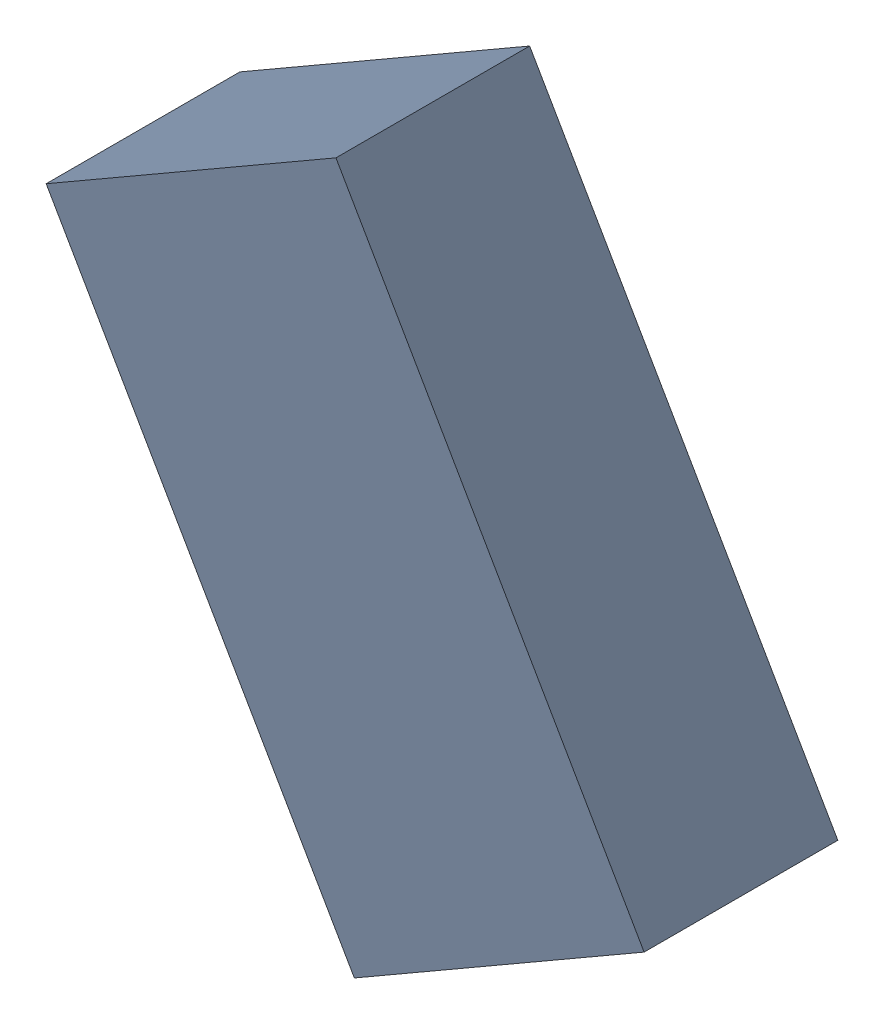
SolidWorks assembly L1_TDA2, configuration Standard. Lengths in mm.
Overall size (1.7 1.99 0.55).
2 component instances, 1 part files, 0 mates.
Components (placement in the parent):
- 885543464-1: 885543464 [Standard] at (47.6154 29.5229 0) size (1.7 1.99 0.55)
  - Extruded_18-1: Extruded_18 [Standard] at origin size (1.7 1.99 0.55)
